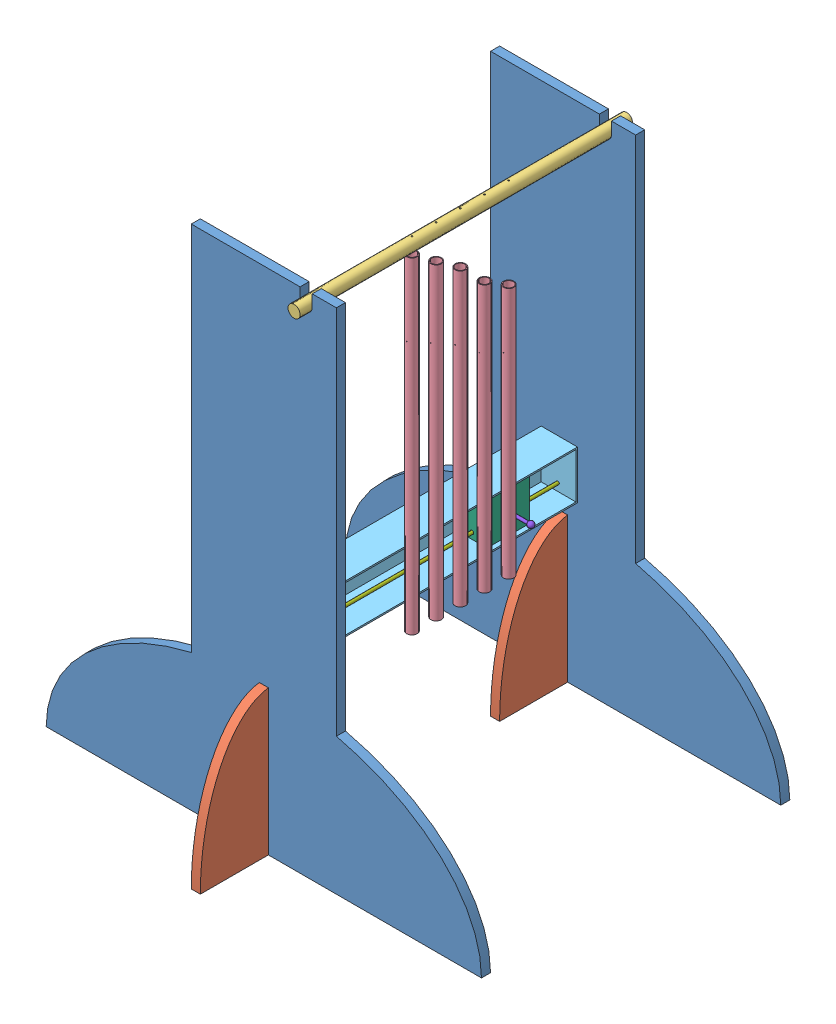
SolidWorks assembly w9-assembly, configuration Default. Lengths in mm.
Overall size (914.4 1073.15 933.45).
16 component instances, 8 part files, 32 mates.
Components (placement in the parent):
- SideSupport-1: SideSupport [Default] at origin size (914.4 1066.8 19.05)
- CrossBrace-1: CrossBrace [Default] x (0 0 1) z (-1 0 0) size (304.8 304.2 19.05)
- dowell-1: dowell [Default] at (88.9 1041.4 34.925) size (25.4 25.4 698.5)
- SideSupport-2: SideSupport [Default] at (0 0 -628.65) size (914.4 1066.8 19.05)
- CrossBrace-2: CrossBrace [Default] at (0 0 -628.65) x (0 0 1) z (-1 0 0) size (304.8 304.2 19.05)
- Pipe1-1: Pipe1 [27] at (88.9 1022.35 -212.725) size (22.23 685.8 22.23)
- Pipe1-2: Pipe1 [25] at (88.9 984.25 -263.525) size (22.23 647.7 22.23)
- Pipe1-3: Pipe1 [24] at (88.9 947.7375 -314.325) size (22.23 611.19 22.23)
- Pipe1-4: Pipe1 [22] at (88.9 896.9375 -365.125) size (22.23 560.39 22.23)
- Pipe1-5: Pipe1 [20] at (88.9 865.1875 -415.925) size (22.23 528.64 22.23)
- w9-BoxAssembly-1: w9-BoxAssembly [Default] at (-7.9375 387.35 -314.325) size (76.2 101.6 609.6) (flexible)
  - BoxFrame-1: BoxFrame [Default] at origin size (76.2 101.6 609.6)
  - BoxStage-1: BoxStage [Default] at (-31.75 0 -165.6288) size (63.5 88.9 88.9)
  - BoxRod-1: BoxRod [Default] at (0 31.75 -304.8) size (6.35 6.35 609.6)
  - BoxRod-2: BoxRod [Default] at (0 -31.75 -304.8) size (6.35 6.35 609.6)
- Clapper-1: Clapper [Default] at (71.4375 387.35 -479.9538) x (1 0 0) z (0 0.610345 -0.792136) size (120.65 12.7 12.7)
Mates (geometry in assembly coordinates):
- Width1: width anti-aligned: plane of CrossBrace-1 through (9.525 304.8 9.525) normal (0 0 -1); plane of CrossBrace-1 through (9.525 304.8 -9.525) normal (0 0 1); plane of SideSupport-1 through (0 0 9.525) normal (0 0 1); plane of SideSupport-1 through (0 0 -9.525) normal (0 0 -1)
- Coincident1: coincident aligned: plane of SideSupport-1 through (-457.2 0 9.525) normal (0 -1 0); plane of CrossBrace-1 through (-9.525 0 -152.4) normal (0 -1 0)
- Coincident2: coincident anti-aligned: plane of SideSupport-1 through (9.525 0 -9.525) normal (-1 0 0); plane of CrossBrace-1 through (9.525 0 0) normal (1 0 0)
- Concentric1: concentric aligned: cylinder of SideSupport-1 through (88.9 1041.4 -9.525) axis (0 0 1) radius 12.7; cylinder of dowell-1 through (88.9 1041.4 -663.575) axis (0 0 1) radius 12.7
- Distance1: distance = 25.4 mm aligned: plane of SideSupport-1 through (0 0 9.525) normal (0 0 1); plane of dowell-1 through (88.9 1041.4 34.925) normal (0 0 1)
- Concentric2: concentric aligned: cylinder of dowell-1 through (88.9 1041.4 -663.575) axis (0 0 1) radius 12.7; cylinder of SideSupport-2 through (88.9 1041.4 -638.175) axis (0 0 1) radius 12.7
- Distance2: distance = 25.4 mm aligned: plane of dowell-1 through (88.9 1041.4 -663.575) normal (0 0 -1); plane of SideSupport-2 through (0 0 -638.175) normal (0 0 -1)
- Coincident5: coincident aligned: plane of SideSupport-1 through (152.4 1066.8 9.525) normal (1 0 0); plane of SideSupport-2 through (152.4 1066.8 -619.125) normal (1 0 0)
- Width2: width aligned: plane of SideSupport-2 through (0 0 -619.125) normal (0 0 1); plane of SideSupport-2 through (0 0 -638.175) normal (0 0 -1); plane of CrossBrace-2 through (9.525 304.8 -638.175) normal (0 0 1); plane of CrossBrace-2 through (9.525 304.8 -619.125) normal (0 0 -1)
- Coincident6: coincident aligned: plane of SideSupport-2 through (-457.2 0 -619.125) normal (0 -1 0); plane of CrossBrace-2 through (-9.525 0 -781.05) normal (0 -1 0)
- Coincident7: coincident anti-aligned: plane of SideSupport-2 through (9.525 0 -638.175) normal (-1 0 0); plane of CrossBrace-2 through (9.525 0 -628.65) normal (1 0 0)
- Parallel1: parallel aligned: plane of SideSupport-1 through (152.4 1066.8 9.525) normal (1 0 0); plane of dowell-1 through (88.9 1041.4 34.925) normal (1 0 0)
- Coincident9: coincident aligned: plane of dowell-1 through (88.9 1041.4 34.925) normal (1 0 0); plane of Pipe1-1 through (88.9 1022.35 -212.725) normal (1 0 0)
- Coincident10: coincident aligned: plane of Pipe1-1 through (88.9 1022.35 -212.725) normal (1 0 0); plane of Pipe1-2 through (88.9 984.25 -263.525) normal (1 0 0)
- Coincident12: coincident aligned: plane of Pipe1-1 through (88.9 1022.35 -212.725) normal (1 0 0); plane of Pipe1-3 through (88.9 947.7375 -314.325) normal (1 0 0)
- Coincident13: coincident aligned: plane of Pipe1-1 through (88.9 1022.35 -212.725) normal (1 0 0); plane of Pipe1-4 through (88.9 896.9375 -365.125) normal (1 0 0)
- Coincident14: coincident aligned: plane of Pipe1-1 through (88.9 1022.35 -212.725) normal (1 0 0); plane of Pipe1-5 through (88.9 865.1875 -415.925) normal (1 0 0)
- Coincident15: coincident aligned: plane of Pipe1-1 through (88.9 336.55 -212.725) normal (0 -1 0); plane of Pipe1-2 through (88.9 336.55 -263.525) normal (0 -1 0)
- Coincident16: coincident aligned: plane of Pipe1-1 through (88.9 336.55 -212.725) normal (0 -1 0); plane of Pipe1-3 through (88.9 336.55 -314.325) normal (0 -1 0)
- Coincident17: coincident aligned: plane of Pipe1-1 through (88.9 336.55 -212.725) normal (0 -1 0); plane of Pipe1-4 through (88.9 336.55 -365.125) normal (0 -1 0)
- Coincident18: coincident aligned: plane of Pipe1-1 through (88.9 336.55 -212.725) normal (0 -1 0); plane of Pipe1-5 through (88.9 336.55 -415.925) normal (0 -1 0)
- Distance3: distance = 50.8 mm aligned: plane of Pipe1-2 through (88.9 984.25 -263.525) normal (0 0 1); plane of Pipe1-1 through (88.9 1022.35 -212.725) normal (0 0 1)
- Distance4: distance = 101.6 mm aligned: plane of Pipe1-1 through (88.9 1022.35 -212.725) normal (0 0 1); plane of Pipe1-3 through (88.9 947.7375 -314.325) normal (0 0 1)
- Distance5: distance = 152.4 mm aligned: plane of Pipe1-4 through (88.9 896.9375 -365.125) normal (0 0 1); plane of Pipe1-1 through (88.9 1022.35 -212.725) normal (0 0 1)
- Distance6: distance = 203.2 mm aligned: plane of Pipe1-5 through (88.9 865.1875 -415.925) normal (0 0 1); plane of Pipe1-1 through (88.9 1022.35 -212.725) normal (0 0 1)
- Distance7: distance = 19.05 mm aligned: plane of dowell-1 through (88.9 1041.4 34.925) normal (0 1 0); plane of Pipe1-1 through (88.9 1022.35 -212.725) normal (0 1 0)
- Concentric3: concentric aligned: cylinder of dowell-1 through (88.9 1028.7 -212.725) axis (0 1 0) radius 1.5875; cylinder of Pipe1-1 through (88.9 336.55 -212.725) axis (0 1 0) radius 11.1125
- Coincident24: coincident anti-aligned: plane of SideSupport-1 through (0 0 -9.525) normal (0 0 -1); plane of w9-BoxAssembly-1/BoxFrame-1 through (30.1625 438.15 -9.525) normal (0 0 1)
- Coincident26: coincident aligned: plane of Pipe1-1 through (88.9 336.55 -212.725) normal (0 -1 0); plane of w9-BoxAssembly-1/BoxFrame-1 through (30.1625 336.55 -619.125) normal (0 -1 0)
- Concentric4: concentric aligned: cylinder of w9-BoxAssembly-1/BoxStage-1 through (-39.6875 387.35 -479.9538) axis (1 0 0) radius 3.175; cylinder of Clapper-1 through (-42.8625 387.35 -479.9538) axis (1 0 0) radius 3.175
- Coincident29: coincident anti-aligned: plane of w9-BoxAssembly-1/BoxFrame-1 through (-42.8625 387.35 -314.325) normal (1 0 0); plane of Clapper-1 through (-42.8625 387.35 -479.9538) normal (-1 0 0)
- Distance8: distance = 11.1125 mm aligned: plane of Pipe1-1 through (88.9 1022.35 -212.725) normal (1 0 0); sphere of Clapper-1
